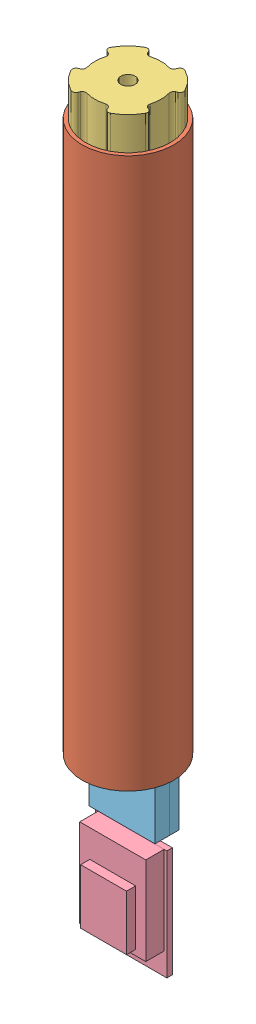
SolidWorks assembly Привод рулонной шторы, configuration По умолчанию. Lengths in mm.
Overall size (35.35 207.49 35.35).
5 component instances, 5 part files, 10 mates.
Components (placement in the parent):
- 16GA-050-12V-30RPM-1: 16GA-050-12V-30RPM [По умолчанию] at origin size (16 59 16)
- Труба 25х1-1: Труба 25х1 [По умолчанию] at (0 -140 0) x (0.718288 0 -0.695746) z (0.695746 0 0.718288) size (25 150 25)
- Вставка-3: Вставка [По умолчанию] at (0 11 0) x (0.707107 0 -0.707107) z (0 1 0) size (23 23 16)
- ESP8266-1: ESP8266 [По умолчанию] at (0 -173.4886 -2.3528) x (-1 0 0) z (0 1 0) size (19.5 11.54 30)
- TB6612-1: TB6612 [По умолчанию] at (0 -145.4486 -2.3528) x (1 0 0) z (0 -1 0) size (18 6.54 21)
Mates (geometry in assembly coordinates):
- Концентричный1: concentric anti-aligned: cylinder of 16GA-050-12V-30RPM-1 through (0 -18 0) axis (0 1 0) radius 8; cylinder of Труба 25х1-1 through (0 10 0) axis (0 -1 0) radius 11.5
- Совпадение1: coincident aligned: plane of 16GA-050-12V-30RPM-1 through (0 10 0) normal (0 1 0); plane of Труба 25х1-1 through (0 10 0) normal (0 1 0)
- Концентричный2: concentric aligned: cylinder of 16GA-050-12V-30RPM-1 through (0 10 0) axis (0 -1 0) radius 1.5; cylinder of Вставка-3 through (0 19 0) axis (0 -1 0) radius 2
- Совпадение5: coincident anti-aligned: plane of 16GA-050-12V-30RPM-1 through (0 3 0) normal (0 1 0); plane of Вставка-3 through (0 3 0) normal (0 -1 0)
- Параллельность1: parallel aligned: plane of 16GA-050-12V-30RPM-1 through (-1.118 3 -1) normal (0 0 -1); plane of Вставка-3
- Параллельность2: parallel anti-aligned: plane of 16GA-050-12V-30RPM-1 through (0 -45 0) normal (0 -1 0); plane of ESP8266-1 through (9.75 -158.4886 -0.8528) normal (0 1 0)
- Расстояние1: distance = 2.54 mm anti-aligned: plane of ESP8266-1 through (9.75 -158.4886 -0.8528) normal (0 1 0); plane of TB6612-1 through (-9 -155.9486 1.6472) normal (0 -1 0)
- Совпадение10: coincident aligned: plane of ESP8266-1 through (0 -173.4886 -4.8928) normal (0 0 -1); plane of TB6612-1 through (0 -145.4486 -4.8928) normal (0 0 -1)
- Совпадение11: coincident anti-aligned: plane of ESP8266-1; plane of TB6612-1
- Совпадение12: coincident anti-aligned: plane of 16GA-050-12V-30RPM-1 through (0 0 0) normal (1 0 0); plane of ESP8266-1
